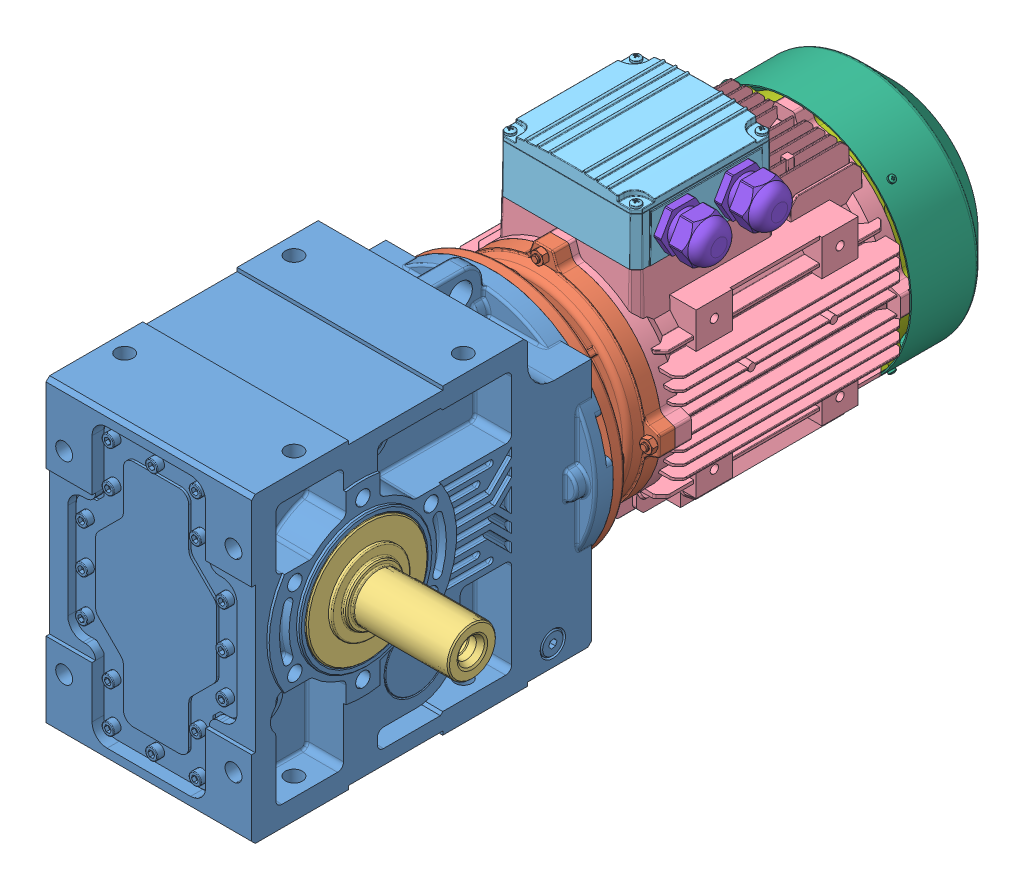
SolidWorks assembly SHRPRO-V1 04 2,2kW Motor KR 373 L3E100L, configuration Predeterminado. Lengths in mm.
Overall size (317.3 286.98 615.8).
8 component instances, 8 part files, 3 mates.
Components (placement in the parent):
- K373_Varsay_lan-1: K373_Varsay_lan [Predeterminado] at (-1000.0001 -985 -948.0001) size (211.14 250 284)
- 333E100_Varsay_lan-1: 333E100_Varsay_lan [Predeterminado] at (-1000.0001 -997.3 -1197.0001) size (200 200 55)
- ML15A_L_Varsay_lan-1: ML15A_L_Varsay_lan [Predeterminado] at (-906.0001 -985 -948.0001) x (1 0 0) z (0 1 0) size (265.5 100 100)
- 3E100L_DA_Varsay_lan-1: 3E100L_DA_Varsay_lan [Predeterminado] at (-1000.0001 -997.3 -1297.0001) size (192 192 200)
- KL_3E100_Varsay_lan-1: KL_3E100_Varsay_lan [Predeterminado] at (-1000.0001 -901.3 -1260.8501) size (116.45 51.17 115.89)
- T_3E100_1_Varsay_lan-1: T_3E100_1_Varsay_lan [Predeterminado] at (-1000.0001 -997.3 -1392.0001) x (0 0 1) z (-0.707107 -0.707107 0) size (81.8 197.71 197.71)
- EF2100A_Varsay_lan-1: EF2100A_Varsay_lan [Predeterminado] at (-1000.0001 -997.3 -1397.0001) x (0 0 -1) z (1 0 0) size (69 193.07 193.07)
- RK_3E100_Varsay_lan-1: RK_3E100_Varsay_lan [Predeterminado] at (-906.5001 -881.3 -1235.8501) x (0 0 1) z (-1 0 0) size (87.5 33.01 45)
Mates (geometry in assembly coordinates):
- Concentric2: concentric: cylinder of K373_Varsay_lan-1 through (-900.0001 -985 -948.0001) axis (-1 0 0) radius 32.5; cylinder of ML15A_L_Varsay_lan-1 through (-1209.7792 -985 -948.0001) axis (-1 0 0) radius 32.5
- Coincident1: coincident: plane of K373_Varsay_lan-1 through (-919.0001 -985 -948.0001) normal (1 0 0); plane of ML15A_L_Varsay_lan-1 through (-919.0001 -985 -948.0001) normal (-1 0 0)
- Parallel1: parallel: plane of K373_Varsay_lan-1 through (-915.0001 -875 -858.0001) normal (0 0 1); plane of ML15A_L_Varsay_lan-1 through (-891.5001 -985 -971.0001) normal (0 0 -1)
